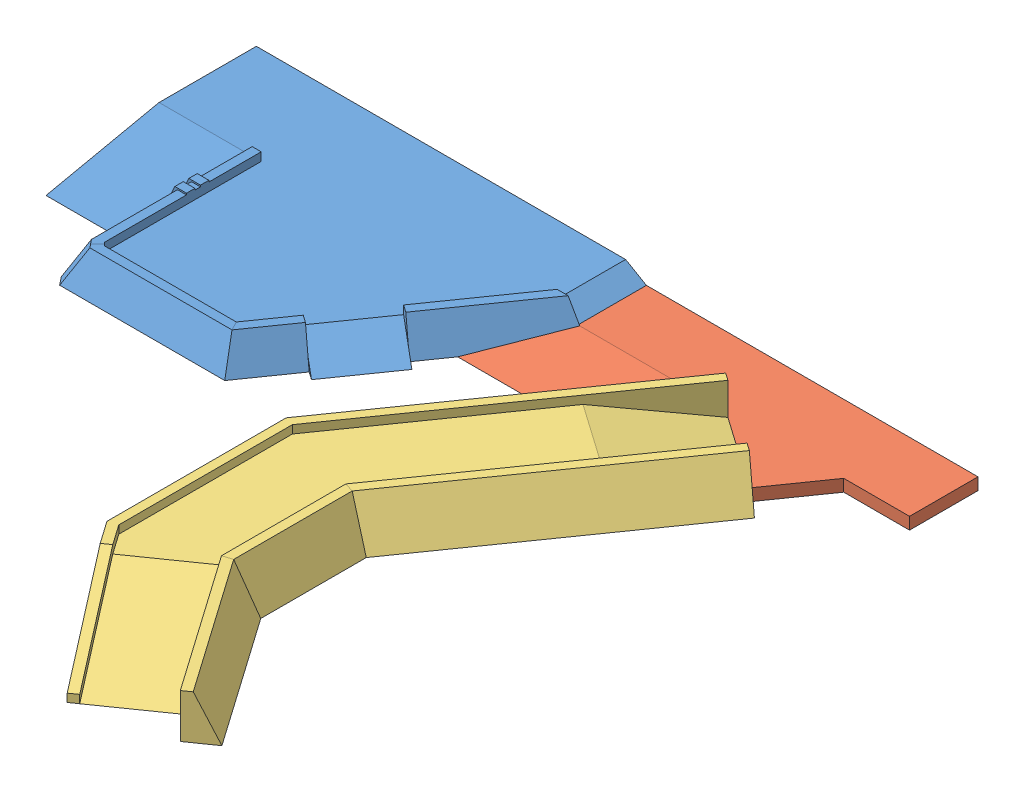
SolidWorks assembly 装配R2R3, configuration 默认. Lengths in mm.
Overall size (12015.41 735 10637.24).
4 component instances, 4 part files, 12 mates.
Components (placement in the parent):
- R3-1: R3 [默认] at (-3595.0327 -658.9044 4497.8203) size (6638.17 564.39 4683.52)
- 公路区-1: 公路区 [默认] at (5659.8774 -658.9044 5067.8203) size (6405.19 200 2402.75)
- R2-1: R2 [默认] at (3795.6377 -658.9044 10399.0699) x (0 0 1) z (-1 0 0) size (9497.24 735 4608.63)
- 小资源岛-1: 小资源岛 [默认] at (3167.286 -658.9044 8768.4514) x (0.819152 0 0.573576) z (-0.573576 0 0.819152) size (265 500 2065)
Mates (geometry in assembly coordinates):
- 重合1: coincident aligned: plane of R3-1 through (-3595.0327 -658.9044 4497.8203) normal (0 -1 0); plane of 公路区-1 through (5659.8774 -658.9044 5067.8203) normal (0 -1 0)
- 重合2: coincident aligned: plane of R3-1 through (-3595.0327 -258.9044 4497.8203) normal (0 0 -1); plane of 公路区-1 through (2899.3774 -458.9044 4497.8203) normal (0 0 -1)
- 重合3: coincident: plane of R3-1 through (3245.7876 -658.9044 5637.8947) normal (0.5 0.866025 0); line of 公路区-1 through (2899.3774 -458.9044 4497.8203) axis (0 0 1)
- 重合5: coincident anti-aligned: plane of 公路区-1 through (5293.2036 -458.9044 5591.4849) normal (-0.573576 0 0.819152); plane of R2-1 through (6547.1479 -58.9044 6469.5062) normal (0.573576 0 -0.819152)
- 重合6: coincident aligned: plane of 公路区-1 through (5659.8774 -658.9044 5067.8203) normal (0 -1 0); plane of R2-1 through (3795.6377 -658.9044 10399.0699) normal (0 -1 0)
- 重合8: coincident anti-aligned: plane of 公路区-1 through (5726.0513 -658.9044 5114.1558) normal (0.819152 0 0.573576); plane of R2-1 through (2345.6377 76.0956 9941.8867) normal (-0.819152 0 -0.573576)
- 重合9: coincident anti-aligned: plane of R2-1 through (2345.6377 76.0956 9941.8867) normal (-0.819152 0 -0.573576); plane of 小资源岛-1 through (3759.5037 -158.9044 7922.6769) normal (0.819152 0 0.573576)
- 重合10: coincident aligned: plane of R2-1 through (3795.6377 -658.9044 10399.0699) normal (0 -1 0); plane of 小资源岛-1 through (3167.286 -658.9044 8768.4514) normal (0 -1 0)
- 距离1: distance = 400 mm: line of 小资源岛-1 through (2575.0683 -158.9044 9614.2258) axis (0 -1 0); line of R2-1 through (2345.6377 76.0956 9941.8867) axis (0 -1 0)
- 距离2: distance = 870.9 mm aligned: plane of R3-1 through (-3595.0327 -658.9044 6118.8203) normal (0 0 -1); plane of 识别块-1 through (-1894.0327 -658.9044 6989.7203) normal (0 0 -1)
- 重合14: coincident aligned: plane of R3-1 through (-1894.0327 -258.9044 9221.5957) normal (1 0 0); plane of 识别块-1 through (-1894.0327 -658.9044 7129.7203) normal (1 0 0)
- 重合15: coincident aligned: plane of R3-1 through (-3595.0327 -658.9044 4497.8203) normal (0 -1 0); plane of 识别块-1 through (-1894.0327 -658.9044 7362.4203) normal (0 -1 0)
